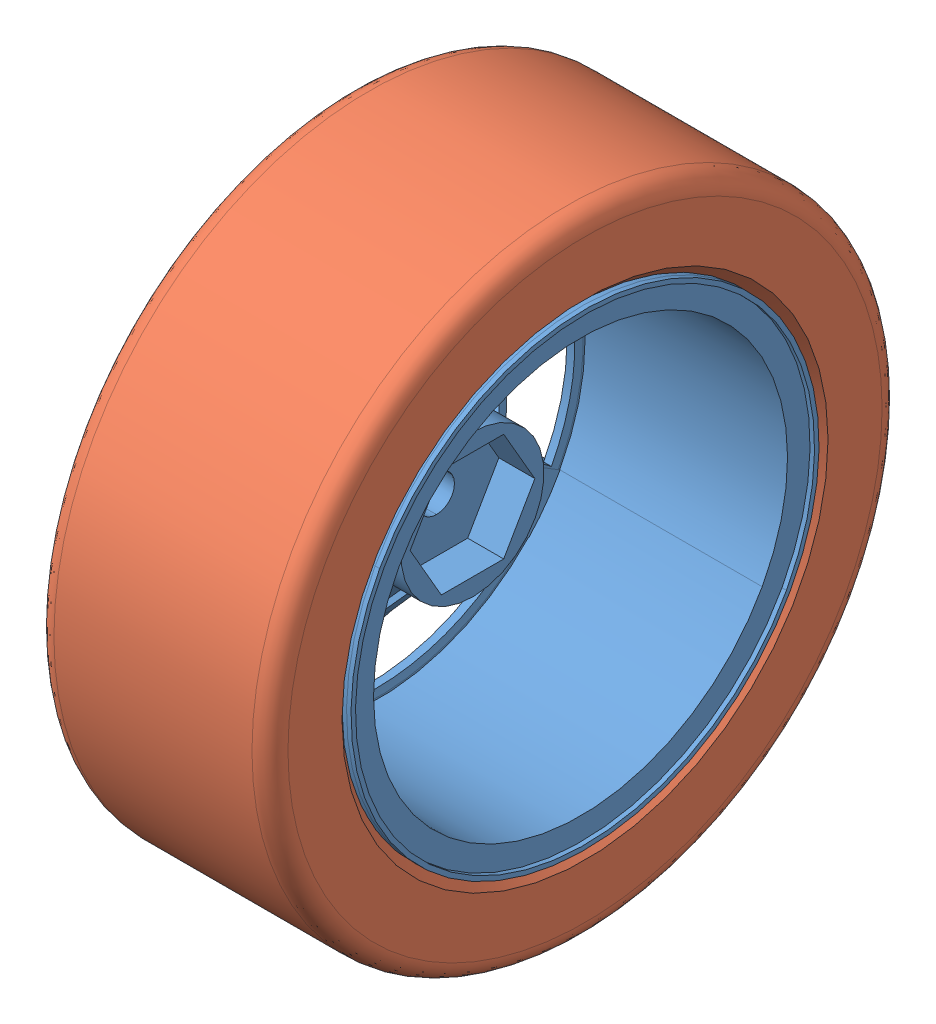
SolidWorks assembly Rueda_Ensamblaje, configuration Predeterminado. Lengths in mm.
Overall size (26 70 70).
2 component instances, 2 part files, 3 mates.
Components (placement in the parent):
- Rim-1: Rim [Predeterminado] at (16.9727 3.5546 94.5) x (0 1 0) z (0 0 1) size (52 26 52)
- llantav2-1: llantav2 [Predeterminado] at (4.4727 3.5546 94.5) x (0 0 -1) z (1 0 0) size (70 70 26)
Mates (geometry in assembly coordinates):
- Concéntrica2: concentric anti-aligned: circle of ?; circle of Rim-1
- Coincidente1: coincident aligned: plane of Rim-1 through (-8.5273 3.5546 120.5) normal (-1 0 0); plane of llantav2-1 through (-8.5273 3.5546 67.5) normal (-1 0 0)
- Concéntrica3: concentric anti-aligned: circle of Rim-1; circle of llantav2-1
